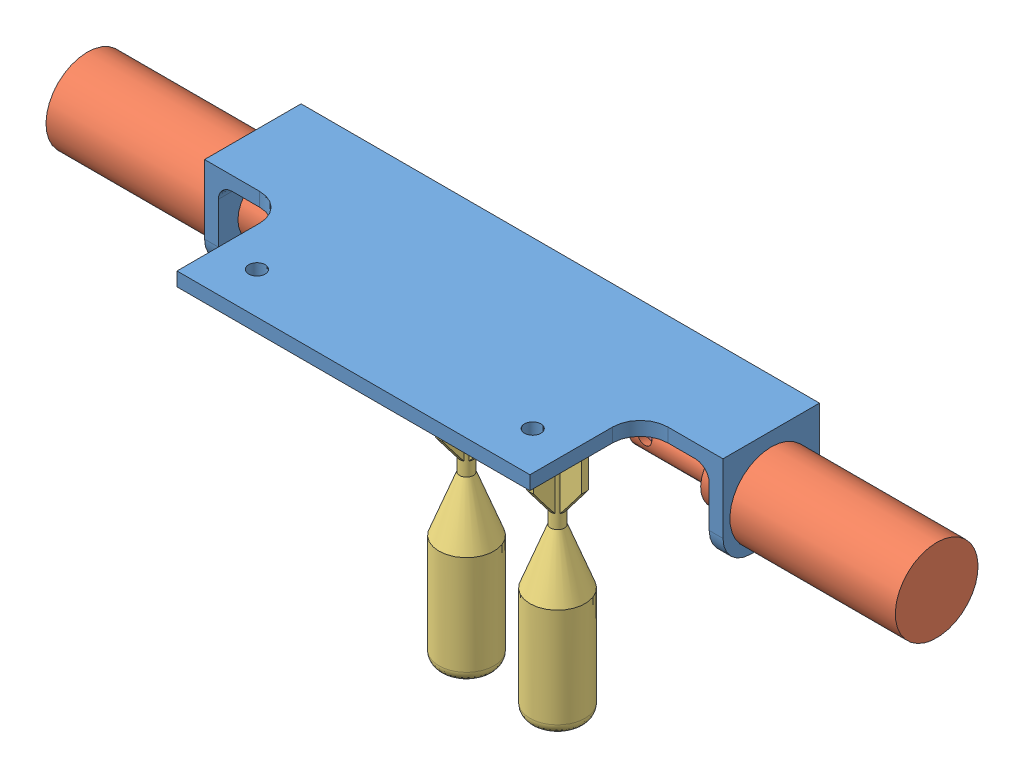
SolidWorks assembly torpedo_bay, configuration Default. Lengths in mm.
Overall size (195.58 81.98 49.92).
7 component instances, 4 part files, 11 mates.
Components (placement in the parent):
- torpedo_bay-1: torpedo_bay [Default] at (-2.0822 -27.8444 35.7091) size (119.38 22.23 47.63)
- solenoid_dropper-1: solenoid_dropper [Default] at (57.6078 -11.9694 35.7091) x (0 -0.981452 0.191707) z (1 0 0) size (19.05 19.05 66.8)
- torpedo-1: torpedo [Default] at (-12.5597 -80.5467 35.7091) size (12.7 72.39 12.7)
- torpedo-2: torpedo [Default] at (8.3953 -80.5467 35.7091) x (-1 0 0) z (0 0 -1) size (12.7 72.39 12.7)
- torpedo pin-1: torpedo pin [Default] at (11.9498 -11.9694 35.7091) x (0 0.461361 0.887212) z (0 0.887212 -0.461361) size (4.57 33.02 4.57)
- torpedo pin-2: torpedo pin [Default] at (-16.1142 -11.6769 35.4353) x (0 0.684501 0.729012) z (0 -0.729012 0.684501) size (4.57 33.02 4.57)
- solenoid_dropper-3: solenoid_dropper [Default] at (-61.7722 -11.9694 35.7091) x (0 0.633707 0.773573) z (-1 0 0) size (19.05 19.05 66.8)
Mates (geometry in assembly coordinates):
- Concentric3: concentric anti-aligned: cylinder of torpedo_bay-1 through (19.5078 -11.9694 35.7091) axis (1 0 0) radius 2.2479; cylinder of torpedo pin-1 through (37.3498 -11.9694 35.7091) axis (-1 0 0) radius 2.286
- Concentric4: concentric aligned: cylinder of torpedo_bay-1 through (-23.6722 -11.9694 35.7091) axis (-1 0 0) radius 2.2479; cylinder of torpedo-1 through (-11.9247 -11.9694 35.7091) axis (-1 0 0) radius 2.54
- Concentric5: concentric anti-aligned: cylinder of torpedo-2 through (7.7603 -11.9694 35.7091) axis (1 0 0) radius 2.54; cylinder of torpedo pin-1 through (37.3498 -11.9694 35.7091) axis (-1 0 0) radius 2.286
- Distance1: distance = 1.5875 mm anti-aligned: plane of torpedo_bay-1 through (16.3328 -2.4444 40.4716) normal (-1 0 0); plane of torpedo-2 through (14.7453 -39.2717 34.9153) normal (1 0 0)
- Distance2: distance = 1.5875 mm anti-aligned: plane of torpedo_bay-1 through (-20.4972 -2.4444 40.4716) normal (1 0 0); plane of torpedo-1 through (-18.9097 -39.2717 36.5028) normal (-1 0 0)
- Parallel3: parallel aligned: plane of torpedo_bay-1 through (-17.3222 -2.4444 24.5966) normal (0 0 -1); plane of torpedo-1 through (-13.3534 -39.2717 29.3591) normal (0 0 -1)
- Parallel4: parallel aligned: plane of torpedo_bay-1 through (-17.3222 -2.4444 24.5966) normal (0 0 -1); plane of torpedo-2 through (7.6016 -39.2717 29.3591) normal (0 0 -1)
- Concentric18: concentric aligned: cylinder of torpedo_bay-1 through (57.6078 -11.9694 35.7091) axis (1 0 0) radius 5.7544; cylinder of solenoid_dropper-1 through (47.9558 -11.9694 35.7091) axis (1 0 0) radius 6.604
- Coincident12: coincident anti-aligned: circle of torpedo_bay-1; plane of solenoid_dropper-1 through (57.6078 -11.9694 35.7091) normal (-1 0 0)
- Concentric19: concentric aligned: cylinder of torpedo_bay-1 through (-61.7722 -11.9694 35.7091) axis (-1 0 0) radius 5.7544; cylinder of solenoid_dropper-3 through (-52.1202 -11.9694 35.7091) axis (-1 0 0) radius 6.604
- Coincident13: coincident anti-aligned: circle of torpedo_bay-1; plane of solenoid_dropper-3 through (-61.7722 -11.9694 35.7091) normal (1 0 0)
